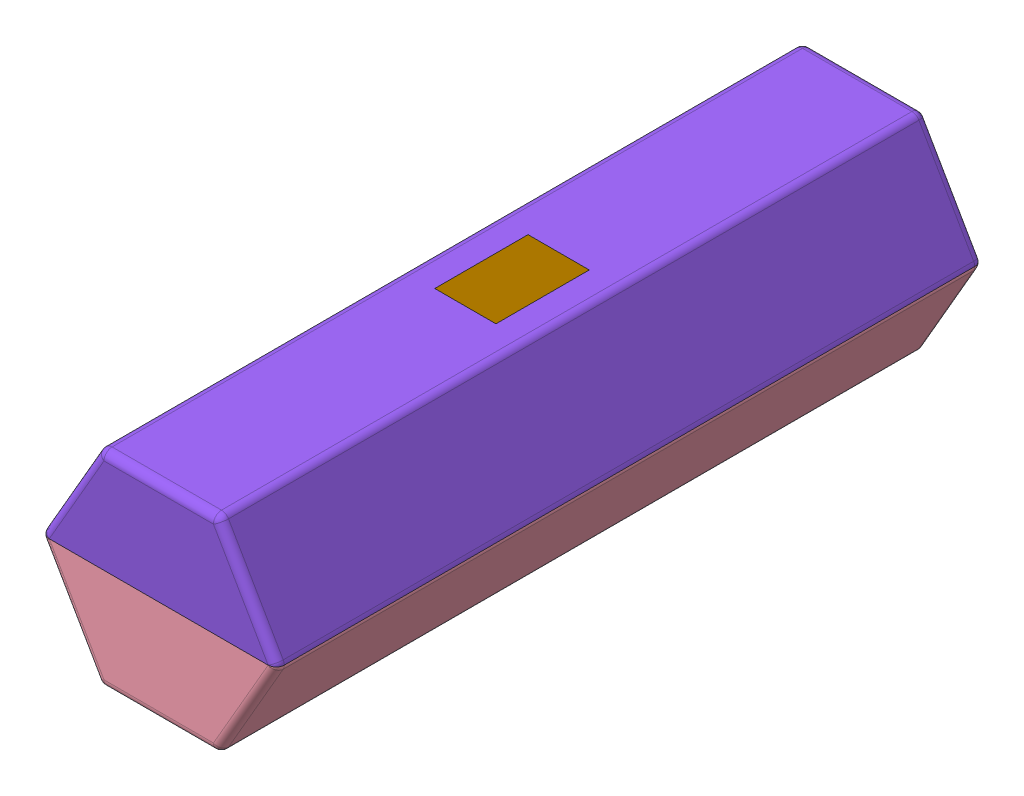
SolidWorks assembly incubator, configuration Default. Lengths in mm.
Overall size (87.17 76.29 264.43).
26 component instances, 14 part files, 28 mates.
Components (placement in the parent):
- eggcrate-2: eggcrate [Default] at (0 0 -1.8281) x (-0.99748 -0.070955 0) z (0 0 1) size (58.31 28.85 221.34)
- egg-1: egg [Default] at (0.0337 -0.4738 -1.8463) x (-0.99748 -0.070955 0) z (0.070955 -0.99748 0) size (45.05 58.24 45.05)
- egg-2: egg [Default] at (0.0337 -0.4738 -71.8463) x (-0.99748 -0.070955 0) z (0.070955 -0.99748 0) size (45.05 58.24 45.05)
- Ball Bearing 608ZZ-1: Ball Bearing 608ZZ [Défaut] at (0 0 6.4734) x (0.935379 0.353646 0) z (0 0 1) size (22 22 7)
- Ball Bearing 608ZZ-2: Ball Bearing 608ZZ [Défaut] at (0 0 -208.5021) x (0.866218 -0.499666 0) z (0 0 -1) size (22 22 7)
- case_botton-1: case_botton [Default] x (1 0 0) z (0 1 0) size (87.17 262.04 38.23)
- FAN for Heat Sink (Hotend)-1: FAN for Heat Sink (Hotend) [Default] at (0 0 -217.0021) x (0 1 0) z (0 0 1) size (31.36 31.11 10)
- cross recessed pan head screws gb-1: cross recessed pan head screws gb [GB_CROSS_SCREWS_TYPE1 M3X14-14  H type-N] at (-12 -12 -224.4021) x (0 0 1) z (-1 0 0) size (16.39 5.6 5.6)
- cross recessed pan head screws gb-2: cross recessed pan head screws gb [GB_CROSS_SCREWS_TYPE1 M3X14-14  H type-N] at (12 -12 -224.4021) x (0 0 1) z (-1 0 0) size (16.39 5.6 5.6)
- heat_element-2: heat_element [Default] at (0 0 -100.9821) size (16.44 27.17 187.54)
- heat_element-3: heat_element [Default] at (0 0 -100.9821) x (-1 0 0) z (0 0 -1) size (16.44 27.17 187.54)
- case_top-2: case_top [Default] x (-1 0 0) z (0 -1 0) size (87.17 262.04 38.15)
- OLED_1.3inch_sh11061b-1: OLED_1.3inch_sh11061b [Default] at (-50.7978 -78.2603 -79.3674) x (0 0 1) z (0 1 0) size (40.5 37.5 11.64)
  - OLED_pcb_1.3_1-1: OLED_pcb_1.3_1 [Default] at (-11.6147 51.3978 113.1661) size (40.5 37.5 3.24)
  - 2.54mm_pin_header_1-1: 2.54mm_pin_header_1 [Default] at (-2.7247 66.9478 113.1661) x (-1 0 0) z (0 0 -1) size (2.54 2.5 11.4)
  - 2.54mm_pin_header_1-2: 2.54mm_pin_header_1 [Default] at (-5.2647 66.9478 113.1661) x (-1 0 0) z (0 0 -1) size (2.54 2.5 11.4)
  - 2.54mm_pin_header_1-3: 2.54mm_pin_header_1 [Default] at (-7.8047 66.9478 113.1661) x (-1 0 0) z (0 0 -1) size (2.54 2.5 11.4)
  - 2.54mm_pin_header_1-4: 2.54mm_pin_header_1 [Default] at (-10.3447 66.9478 113.1661) x (-1 0 0) z (0 0 -1) size (2.54 2.5 11.4)
  - 2.54mm_pin_header_1-5: 2.54mm_pin_header_1 [Default] at (-12.8847 66.9478 113.1661) x (-1 0 0) z (0 0 -1) size (2.54 2.5 11.4)
  - 2.54mm_pin_header_1-6: 2.54mm_pin_header_1 [Default] at (-15.4247 66.9478 113.1661) x (-1 0 0) z (0 0 -1) size (2.54 2.5 11.4)
  - 2.54mm_pin_header_1-7: 2.54mm_pin_header_1 [Default] at (-17.9647 66.9478 113.1661) x (-1 0 0) z (0 0 -1) size (2.54 2.5 11.4)
  - 2.54mm_pin_header_1-8: 2.54mm_pin_header_1 [Default] at (-20.5047 66.9478 113.1661) x (-1 0 0) z (0 0 -1) size (2.54 2.5 11.4)
- servo motor smaller-1: servo motor smaller [Valor predeterminado] at (4.3 -4.3 32.9734) x (0 1 0) z (-1 0 0) size (30.65 25 8.6)
- water-1: water [Default] at origin size (20 6 186.04)
- termistor-1: termistor [Default] at origin size (1 6.28 1)
- DHT22-1: DHT22 [Default] at (0.6 36.2958 -58.1571) x (0 -1 0) z (-1 0 0) size (8.15 32.95 15.47)
Mates (geometry in assembly coordinates):
- Concentric7: concentric anti-aligned: cylinder of support^WWEGGSLDASM-2 through (0 0 10.4734) axis (0 0 1) radius 4; cylinder of Ball Bearing 608ZZ-2 through (0 0 -443.5523) axis (0 0 -1) radius 4
- Concentric10: concentric anti-aligned: cylinder of support^WWEGGSLDASM-2 through (0 0 10.4734) axis (0 0 1) radius 4; cylinder of Case botton-1 through (0 0 10.0379) axis (0 0 -1) radius 11
- Coincident15: coincident: curve of support^WWEGGSLDASM-2; point of Egg WWE-1
- Lock3: lock: unknown of eggcrate-2; unknown of egg-1
- Coincident16: coincident: point of support^WWEGGSLDASM-2; point of Egg WWE-2
- Lock4: lock: unknown of eggcrate-2; unknown of egg-2
- Concentric11: concentric aligned: circle of support^WWEGGSLDASM-2; circle of FAN for Heat Sink (Hotend)-1
- Parallel1: parallel: plane of assembly; plane of case_botton-1 through (44.047 0 40.0379) normal (0 1 0); plane of FAN for Heat Sink (Hotend)-1 through (6.485 15 -214.0021) normal (0 1 0)
- Coincident19: coincident aligned: plane of Case botton-1 through (0 0 -222.0021) normal (0 0 -1); plane of FAN for Heat Sink (Hotend)-1 through (15 15 -222.0021) normal (0 0 -1)
- Concentric13: concentric aligned: cylinder of FAN for Heat Sink (Hotend)-1 through (-12 -12 -222.0021) axis (0 0 1) radius 1.6; cylinder of cross recessed pan head screws gb-1 through (-12 -12 -219.8863) axis (0 0 1) radius 2.8
- Coincident21: coincident anti-aligned: plane of FAN for Heat Sink (Hotend)-1 through (15 15 -222.0021) normal (0 0 -1); plane of cross recessed pan head screws gb-1 through (-12 -10.2 -222.0021) normal (0 0 1)
- Concentric14: concentric aligned: cylinder of FAN for Heat Sink (Hotend)-1 through (12 -12 -222.0021) axis (0 0 1) radius 1.6; cylinder of cross recessed pan head screws gb-2 through (12 -12 -219.8863) axis (0 0 1) radius 2.8
- Coincident22: coincident anti-aligned: plane of FAN for Heat Sink (Hotend)-1 through (15 15 -222.0021) normal (0 0 -1); plane of cross recessed pan head screws gb-2 through (12 -10.2 -222.0021) normal (0 0 1)
- Concentric16: concentric aligned: circle of Ball Bearing 608ZZ-1; cylinder of servo motor smaller-1 through (0 0 7.9734) axis (0 0 1) radius 0.75
- Distance1: distance = 1 mm anti-aligned: plane of servo motor smaller-1 through (4.3 -4.3 10.9734) normal (0 0 -1); plane of Ball Bearing 608ZZ-1 through (0 0 9.9734) normal (0 0 1)
- Parallel7: parallel aligned: plane of Case botton-1 through (22.0235 -38.1458 10.0379) normal (0 -1 0); plane of servo motor smaller-1 through (-4.3 -4.3 32.9734) normal (0 -1 0)
- Coincident30: coincident: point of support^WWEGGSLDASM-2; plane of Ball Bearing 608ZZ-2 through (-2.973 -5.154 -205.1021) normal (0 0 1)
- Concentric17: concentric aligned: cylinder of support^WWEGGSLDASM-2 through (0 0 10.4734) axis (0 0 1) radius 4; cylinder of Ball Bearing 608ZZ-1 through (0 0 241.5237) axis (0 0 1) radius 4
- Coincident31: coincident: point of support^WWEGGSLDASM-2; plane of Ball Bearing 608ZZ-1 through (-2.1042 5.5655 3.0734) normal (0 0 -1)
- Coincident32: coincident anti-aligned: plane of Ball Bearing 608ZZ-2 through (0 0 -212.0021) normal (0 0 -1); circle of Case botton-1
- Coincident33: coincident: plane of Case botton-1 through (44.047 0 40.0379) normal (0 1 0); plane of case_top-2 through (-44.047 0 40.0379) normal (0 -1 0)
- Coincident34: coincident: plane of Case botton-1 through (0 0 -212.0021) normal (0 0 -1); plane of case_top-2 through (0 0 -212.0021) normal (0 0 -1)
- Coincident35: coincident: line of Case botton-1 through (43.5829 0 -219.0021) axis (0 0 1); line of case_top-2 through (43.5829 0 37.0379) axis (0 0 -1)
- Concentric18: concentric anti-aligned: cylinder of case_top-2 through (31.5371 3.1679 -100.9821) axis (0 0 -1) radius 0.75; cylinder of Resistence-2 through (31.5371 3.1679 -100.9821) axis (0 0 1) radius 0.75
- Concentric19: concentric aligned: cylinder of case_top-2 through (27.7833 9.6695 -103.9821) axis (-0.5 0.866025 0) radius 0.75; cylinder of Resistence-2 through (27.7833 9.6695 -103.9821) axis (-0.5 0.866025 0) radius 0.75
- Coincident36: coincident aligned: plane of case_top-2 through (-16.25 28.1458 10.0379) normal (0 -1 0); plane of DHT22-1 through (0.6 28.1458 -58.1571) normal (0 -1 0)
- Coincident37: coincident aligned: plane of case_top-2 through (17.35 34.9058 -70.7321) normal (0 0 -1); plane of DHT22-1 through (0.6 28.1458 -70.7321) normal (0 0 -1)
- Width1: width anti-aligned: plane of case_top-2 through (-18.15 34.9058 -109.2321) normal (1 0 0); plane of case_top-2 through (19.35 36.5458 -109.2321) normal (-1 0 0); plane of DHT22-1 through (-7.135 28.1458 -58.1571) normal (-1 0 0); plane of DHT22-1 through (8.335 28.1458 -58.1571) normal (1 0 0)
